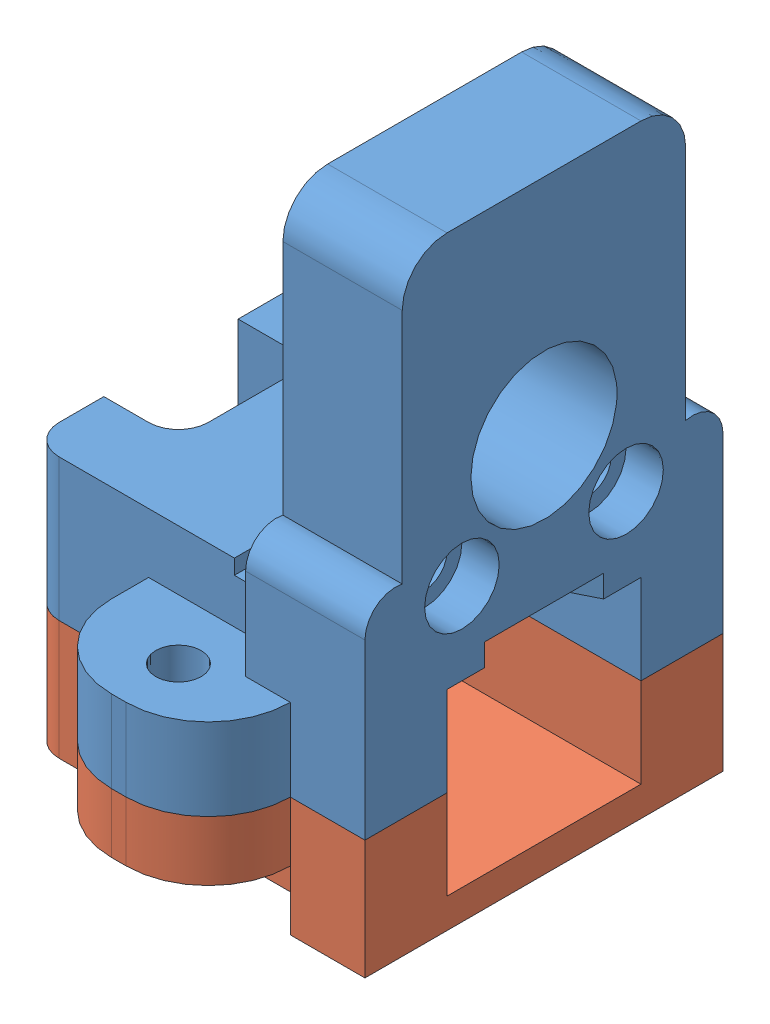
SolidWorks assembly Assem2, configuration Default. Lengths in mm.
Overall size (25 40.5 35).
2 component instances, 2 part files, 3 mates.
Components (placement in the parent):
- Top_Bracket_rev2-1: Top_Bracket_rev2 [Default] at (-3.0956 14.9109 37.6716) size (25 32.5 35)
- Bottom_Bracket_rev2-1: Bottom_Bracket_rev2 [Default] at (-3.0956 14.9109 24.6716) x (1 0 0) z (0 0 -1) size (25 8 35)
Mates (geometry in assembly coordinates):
- Coincident1: coincident aligned: plane of Top_Bracket_rev2-1 through (-6.0956 20.9109 38.6716) normal (-1 0 0); plane of Bottom_Bracket_rev2-1 through (-6.0956 8.9109 23.6716) normal (-1 0 0)
- Concentric1: concentric anti-aligned: circle of Top_Bracket_rev2-1; circle of Bottom_Bracket_rev2-1
- Coincident2: coincident anti-aligned: plane of Top_Bracket_rev2-1 through (-4.0956 14.9109 23.6716) normal (0 -1 0); plane of Bottom_Bracket_rev2-1 through (-4.0956 14.9109 23.6716) normal (0 1 0)
